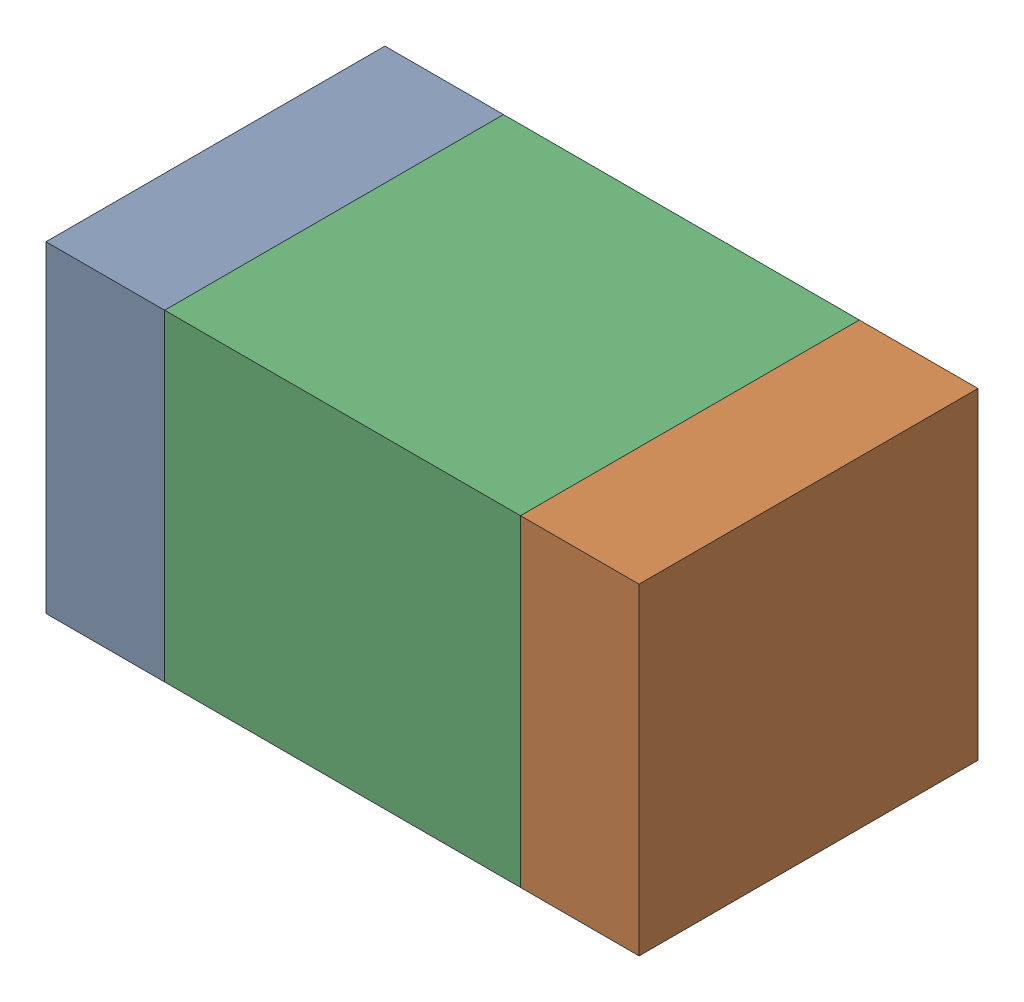
SolidWorks assembly C5-2, configuration Default. Lengths in mm.
Overall size (1.75 0.95 1).
6 component instances, 2 part files, 0 mates.
Components (placement in the parent):
- 959208936-2-1: 959208936-2 [Default] at (142.772 80.518 0) size (0.35 0.95 1)
  - Extruded-78-1: Extruded-78 [Default] at origin size (0.35 0.95 1)
- 959208936-2-2: 959208936-2 [Default] at (144.172 80.518 0) size (0.35 0.95 1)
  - Extruded-78-1: Extruded-78 [Default] at origin size (0.35 0.95 1)
- 959208800-2-1: 959208800-2 [Default] at (143.472 80.518 0) size (1.05 0.95 1)
  - Extruded-79-1: Extruded-79 [Default] at origin size (1.05 0.95 1)
